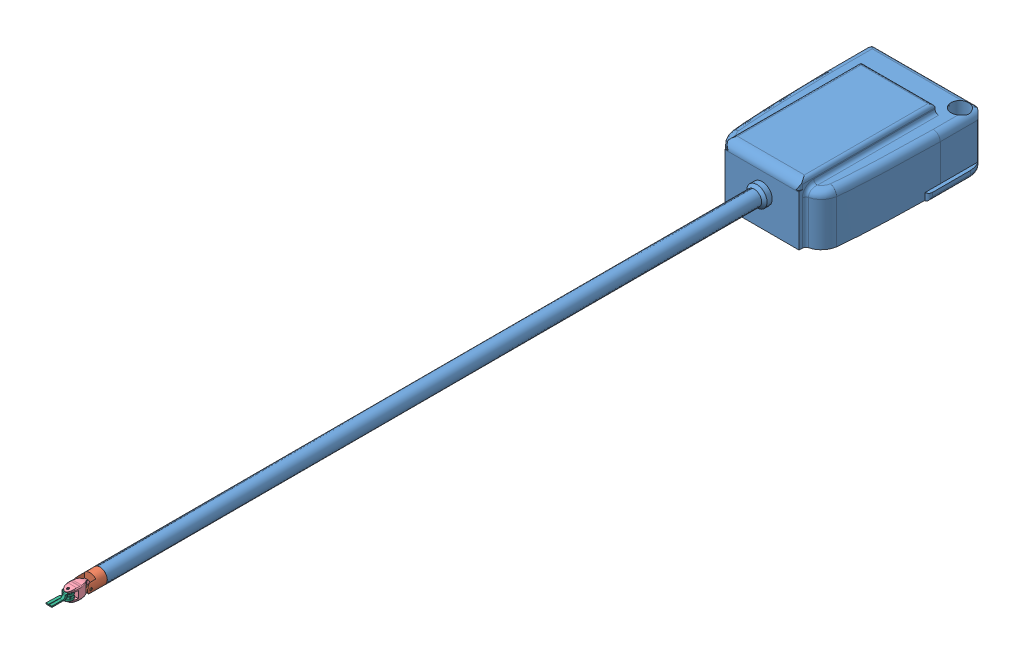
SolidWorks assembly Small_Clipper_Applier, configuration Default. Lengths in mm.
Overall size (68.49 33 492.67).
7 component instances, 6 part files, 14 mates.
Components (placement in the parent):
- Tool_main-1: Tool_main [Default] at (23.4042 -4.4936 -143.5876) size (68.49 33 464)
- Tool_Wrists_Link_1-1: Tool_Wrists_Link_1 [Default] at (23.4042 -4.4936 223.2124) size (8.32 8.32 11)
- Tool_Wrists_Shaft_Link_1_2-1: Tool_Wrists_Shaft_Link_1_2 [Default] at (27.3042 -4.4936 232.3124) x (0 -0.980722 0.195408) z (-1 0 0) size (1.3 1.3 8.02)
- Tool_Wristis_Small_Clip_Applier_Link_2-1: Tool_Wristis_Small_Clip_Applier_Link_2 [Default] at (23.6042 -7.6936 237.4124) x (0 0 -1) z (0 1 0) size (13.22 7.35 6.88)
- Tool_Wristis_Small_Clip_Applier_shaft_Link_2_3-1: Tool_Wristis_Small_Clip_Applier_shaft_Link_2_3 [Default] at (23.6042 -7.0936 241.2124) x (0.98943 0 -0.145014) z (0 1 0) size (1.3 1.3 5)
- Tool_Wristis_Small_Clip_Applier_Link_3-1: Tool_Wristis_Small_Clip_Applier_Link_3 [Default] at (23.6042 -4.8436 241.2124) x (0.999503 0 0.031531) z (0 -1 0) size (5 13.1 2.29)
- Tool_Wristis_Small_Clip_Applier_Link_3-2: Tool_Wristis_Small_Clip_Applier_Link_3 [Default] at (23.6042 -4.2536 241.2124) x (-1 0 0) z (0 1 0) size (5 13.1 2.29)
Mates (geometry in assembly coordinates):
- Concentric1: concentric aligned: circle of Tool_main-1; circle of Tool_Wrists_Link_1-1
- Coincident1: coincident anti-aligned: plane of Tool_main-1 through (23.4042 -4.4936 223.2124) normal (0 0 1); plane of Tool_Wrists_Link_1-1 through (23.4042 -4.4936 223.2124) normal (0 0 -1)
- Concentric2: concentric anti-aligned: circle of Tool_Wrists_Link_1-1; cylinder of Tool_Wrists_Shaft_Link_1_2-1
- Concentric3: concentric aligned: circle of Tool_Wrists_Link_1-1; cylinder of Tool_Wristis_Small_Clip_Applier_Link_2-1
- Distance1: distance = 2 mm anti-aligned: plane of Tool_Wristis_Small_Clip_Applier_Link_2-1 through (24.6042 -1.3936 229.9124) normal (1 0 0); plane of Tool_Wrists_Link_1-1 through (26.6042 -8.6536 235.0698) normal (-1 0 0)
- Distance2: distance = 7.1 mm aligned: plane of Tool_Wrists_Shaft_Link_1_2-1 through (27.3042 -4.4936 232.3124) normal (1 0 0); plane of Tool_Wrists_Link_1-1 through (20.2042 -8.6536 235.0698) normal (1 0 0)
- Coincident4: coincident anti-aligned: circle of Tool_Wristis_Small_Clip_Applier_Link_2-1; cylinder of Tool_Wristis_Small_Clip_Applier_shaft_Link_2_3-1
- Distance3: distance = 4.5 mm aligned: plane of Tool_Wristis_Small_Clip_Applier_shaft_Link_2_3-1 through (23.6042 -7.0936 241.2124) normal (0 -1 0); plane of Tool_Wristis_Small_Clip_Applier_Link_2-1 through (27.2795 -2.5936 243.4124) normal (0 -1 0)
- Concentric4: concentric aligned: circle of Tool_Wristis_Small_Clip_Applier_Link_2-1; circle of Tool_Wristis_Small_Clip_Applier_Link_3-2
- Distance7: distance = 0.01 mm anti-aligned: plane of Tool_Wristis_Small_Clip_Applier_Link_3-2 through (23.6042 -2.6036 241.2124) normal (0 1 0); plane of Tool_Wristis_Small_Clip_Applier_Link_2-1 through (27.2795 -2.5936 243.4124) normal (0 -1 0)
- Concentric5: concentric anti-aligned: circle of Tool_Wristis_Small_Clip_Applier_Link_2-1; circle of Tool_Wristis_Small_Clip_Applier_Link_3-1
- Coincident16: coincident anti-aligned: plane of Tool_Wristis_Small_Clip_Applier_Link_3-1 through (23.6042 -6.4936 241.2124) normal (0 -1 0); plane of Tool_Wristis_Small_Clip_Applier_Link_2-1 through (27.2795 -6.4936 243.4124) normal (0 1 0)
- Parallel1: parallel aligned: plane of Tool_main-1 through (57.5042 11.2564 -240.7876) normal (0 1 0); plane of Tool_Wristis_Small_Clip_Applier_Link_3-1 through (21.7707 -4.2436 251.7598) normal (0 1 0)
- Parallel2: parallel aligned: plane of Tool_main-1 through (55.5042 17.7861 223.2124) normal (1 0 0); plane of Tool_Wristis_Small_Clip_Applier_Link_3-2 through (25.1042 -2.6536 251.8124) normal (1 0 0)
